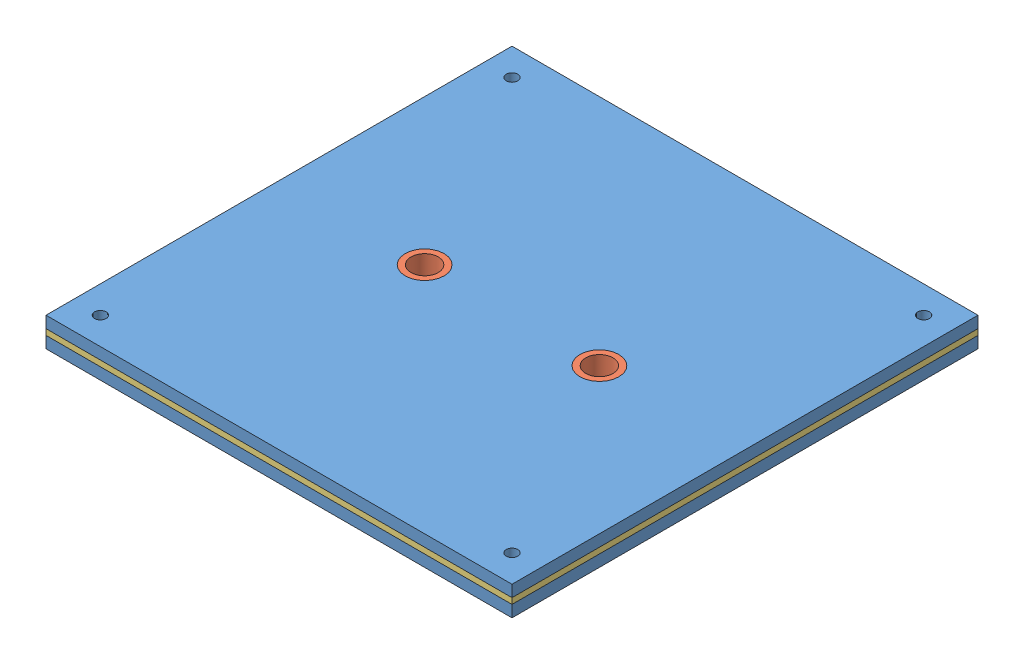
SolidWorks assembly through_all, configuration Default. Lengths in mm.
Overall size (120 7.5 120).
5 component instances, 3 part files, 6 mates.
Components (placement in the parent):
- lower_upper_layer - THROUGH ALL-1: lower_upper_layer - THROUGH ALL [Default] at (-13.5764 118.5 0.8517) size (120 3 120)
- ring_through_all-1: ring_through_all [Default] at (-36.0764 118.5 0.8517) size (10 7.5 10)
- ring_through_all-2: ring_through_all [Default] at (8.9236 118.5 0.8517) size (10 7.5 10)
- middle_layer-1: middle_layer [Default] at (-13.5764 121.5 0.8517) size (120 1.5 120)
- lower_upper_layer - THROUGH ALL-2: lower_upper_layer - THROUGH ALL [Default] at (-13.5764 123 0.8517) size (120 3 120)
Mates (geometry in assembly coordinates):
- Coincident2: coincident aligned: circle of lower_upper_layer - THROUGH ALL-1; circle of ring_through_all-1
- Coincident3: coincident aligned: circle of lower_upper_layer - THROUGH ALL-1; circle of ring_through_all-2
- Coincident4: coincident: line of lower_upper_layer - THROUGH ALL-1 through (-73.5764 121.5 60.8517) axis (1 0 0); line of middle_layer-1 through (-73.5764 121.5 60.8517) axis (1 0 0)
- Coincident5: coincident aligned: line of lower_upper_layer - THROUGH ALL-1 through (46.4236 121.5 60.8517) axis (0 0 -1); line of middle_layer-1 through (46.4236 121.5 60.8517) axis (0 0 -1)
- Coincident6: coincident: line of middle_layer-1 through (46.4236 123 60.8517) axis (0 0 -1); line of lower_upper_layer - THROUGH ALL-2 through (46.4236 123 60.8517) axis (0 0 -1)
- Coincident7: coincident aligned: line of middle_layer-1 through (-73.5764 123 60.8517) axis (1 0 0); line of lower_upper_layer - THROUGH ALL-2 through (-73.5764 123 60.8517) axis (1 0 0)
